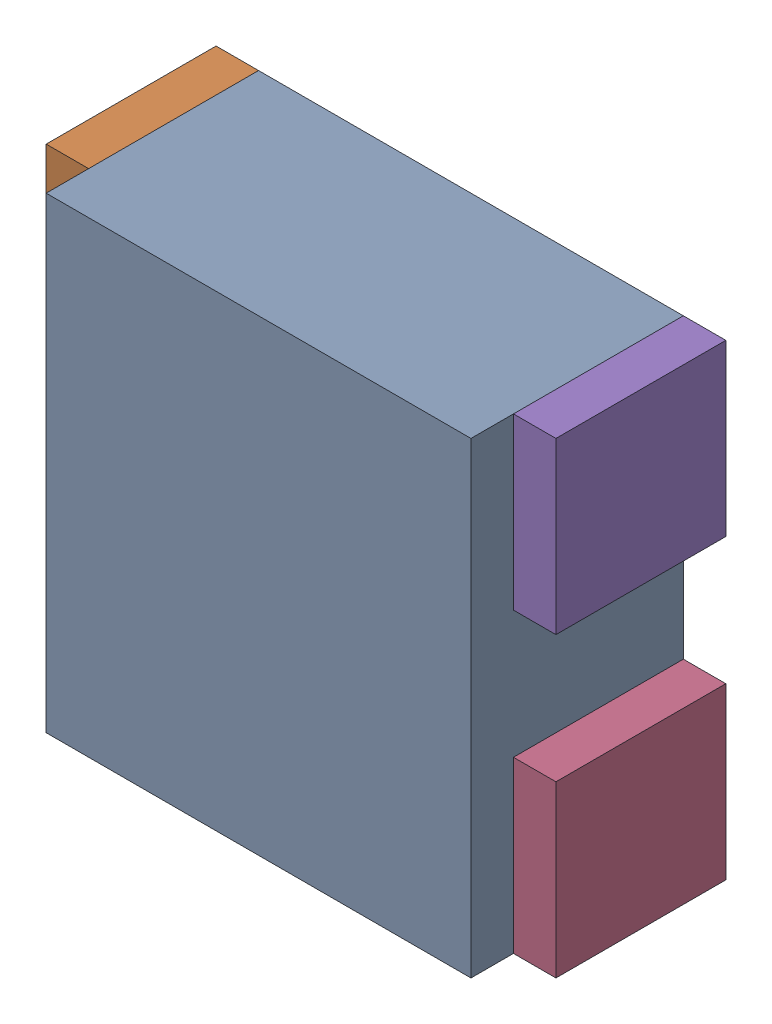
SolidWorks assembly RN11, configuration Default. Lengths in mm.
Overall size (1.2 1.1 0.5).
10 component instances, 2 part files, 0 mates.
Components (placement in the parent):
- 836749552-1: 836749552 [Default] at (118.7 53.25 0) size (1 1.1 0.5)
  - Extruded_11-1: Extruded_11 [Default] at origin size (1 1.1 0.5)
- 791587232-1: 791587232 [Default] at (118.15 53.6 0) size (0.1 0.4 0.4)
  - Extruded_10-1: Extruded_10 [Default] at origin size (0.1 0.4 0.4)
- 791587232-2: 791587232 [Default] at (118.15 52.9 0) size (0.1 0.4 0.4)
  - Extruded_10-1: Extruded_10 [Default] at origin size (0.1 0.4 0.4)
- 791587232-3: 791587232 [Default] at (119.25 52.9 0) size (0.1 0.4 0.4)
  - Extruded_10-1: Extruded_10 [Default] at origin size (0.1 0.4 0.4)
- 791587232-4: 791587232 [Default] at (119.25 53.6 0) size (0.1 0.4 0.4)
  - Extruded_10-1: Extruded_10 [Default] at origin size (0.1 0.4 0.4)
